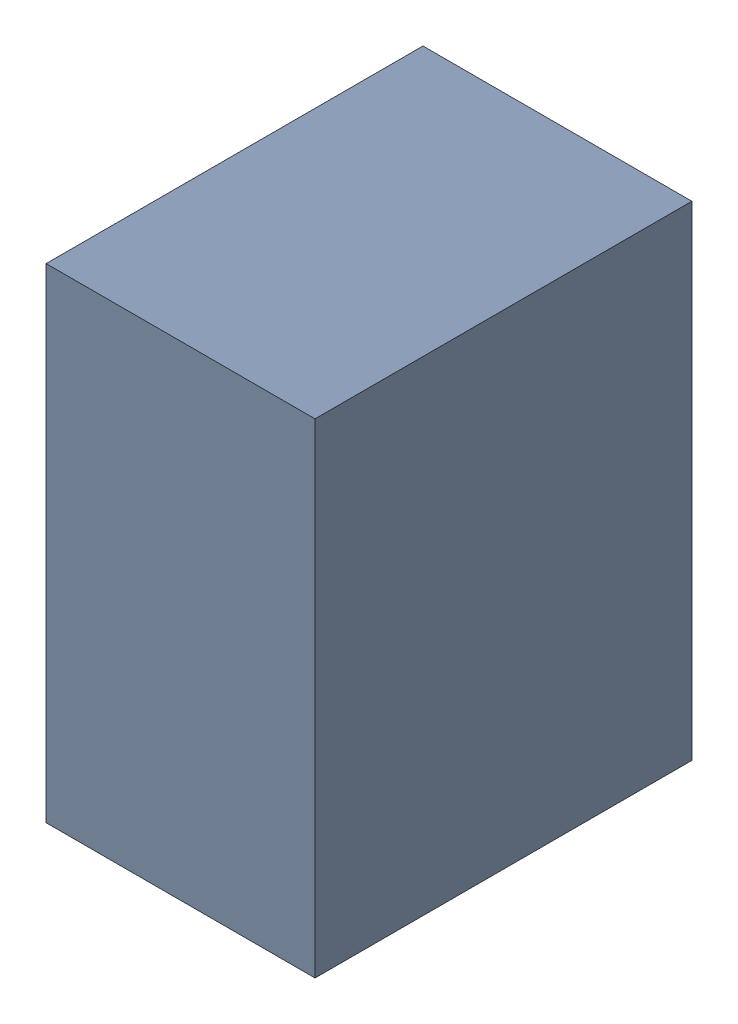
SolidWorks assembly C15, configuration Default. Lengths in mm.
Overall size (1 1.8 1.4).
3 component instances, 2 part files, 0 mates.
Components (placement in the parent):
- 1088883208-1: 1088883208 [Default] at (12.425 22.1 0) size (1 1.8 1.4)
  - Extruded-45-1: Extruded-45 [Default] at origin size (1 1.8 1.4)
- C0603-1: C0603 [Default] at (12.0249 22.9001 0) x (0 -1 0) z (-1 0 0) size (1.6 0.5 0.8)
